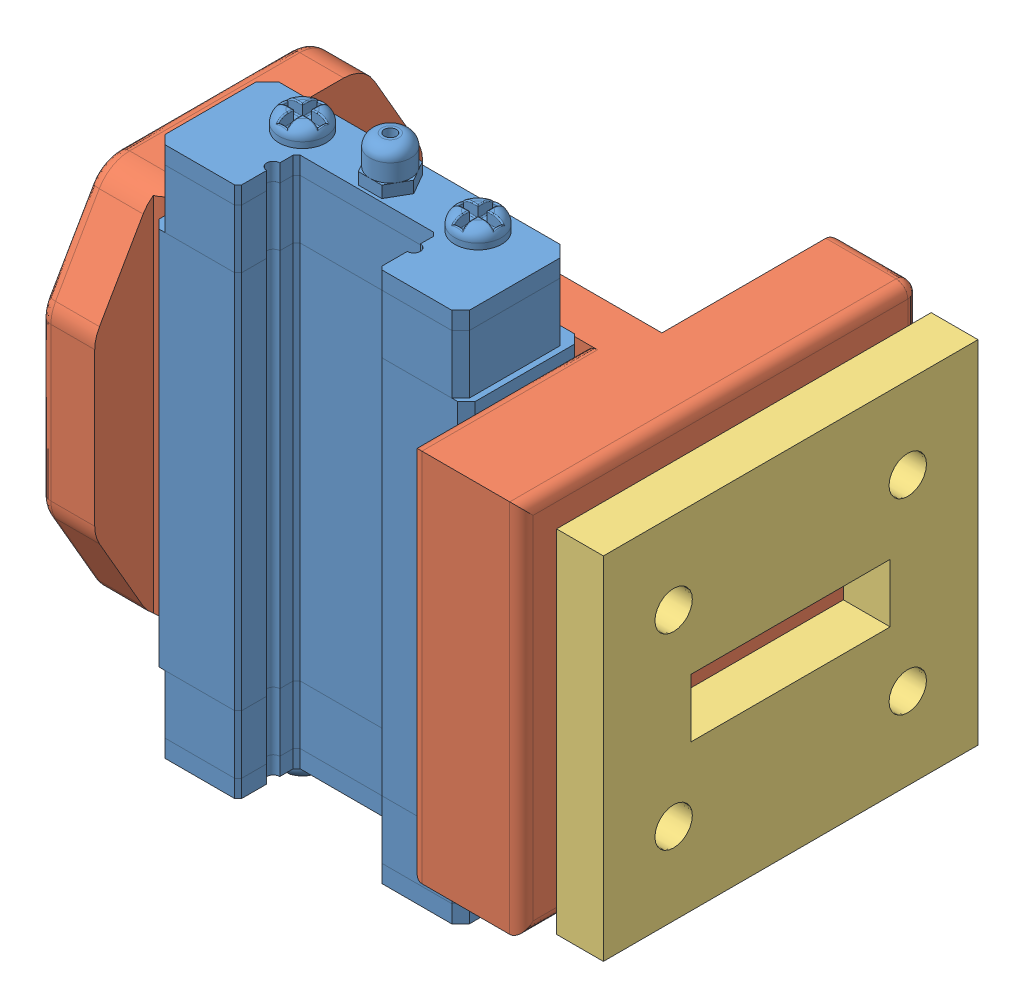
SolidWorks assembly Ползун с зажимом, configuration По умолчанию. Lengths in mm.
Overall size (50.2 50.47 34).
3 component instances, 3 part files, 9 mates.
Components (placement in the parent):
- Ползун-1: Ползун [Default] at (0 6.5 13) x (1 0 0) z (0 1 0) size (27 10 50.47)
- Тавр обрезаный-1: Тавр обрезаный [По умолчанию] at (18 6.7 0) x (-1 0 0) z (0 0 -1) size (44.2 32 34)
- Прижимная планка 3-2: Прижимная планка 3 [По умолчанию] at (9.7261 -0.7936 0.7637) size (4 30 33)
Mates (geometry in assembly coordinates):
- Совпадение1: coincident anti-aligned: plane of Ползун-1 through (-13.5 38.9 0) normal (0 0 -1); plane of assembly through (0 0 0) normal (0 0 1)
- Совпадение2: coincident anti-aligned: plane of Ползун-1; plane of assembly through (0 0 0) normal (1 0 0)
- Совпадение3: coincident anti-aligned: plane of Ползун-1 through (6 0 7) normal (0 -1 0); plane of assembly through (0 0 0) normal (0 1 0)
- Концентричный1: concentric anti-aligned: cylinder of Ползун-1 through (-10 32.7 0) axis (0 0 -1) radius 1.25; cylinder of Тавр обрезаный-1 through (-10 32.7 -4) axis (0 0 1) radius 1.6
- Концентричный2: concentric anti-aligned: cylinder of Ползун-1 through (10 12.7 0) axis (0 0 -1) radius 1.25; cylinder of Тавр обрезаный-1 through (10 12.7 -4) axis (0 0 1) radius 1.6
- Совпадение4: coincident anti-aligned: plane of Ползун-1 through (-13.5 38.9 0) normal (0 0 -1); plane of Тавр обрезаный-1 through (18 6.7 0) normal (0 0 1)
- Concentric3: concentric aligned: cylinder of Тавр обрезаный-1 through (23.2 30.7 -12) axis (-1 0 0) radius 1.6; cylinder of Прижимная планка 3-2 through (29.2 30.7 -12) axis (-1 0 0) radius 1.6
- Concentric4: concentric aligned: cylinder of Тавр обрезаный-1 through (23.2 14.7 8) axis (-1 0 0) radius 1.6; cylinder of Прижимная планка 3-2 through (29.2 14.7 8) axis (-1 0 0) radius 1.6
- Coincident3: coincident anti-aligned: plane of Прижимная планка 3-2 through (25.2 -0.7936 0.7637) normal (-1 0 0); plane of assembly through (25.2 0 0) normal (1 0 0)
